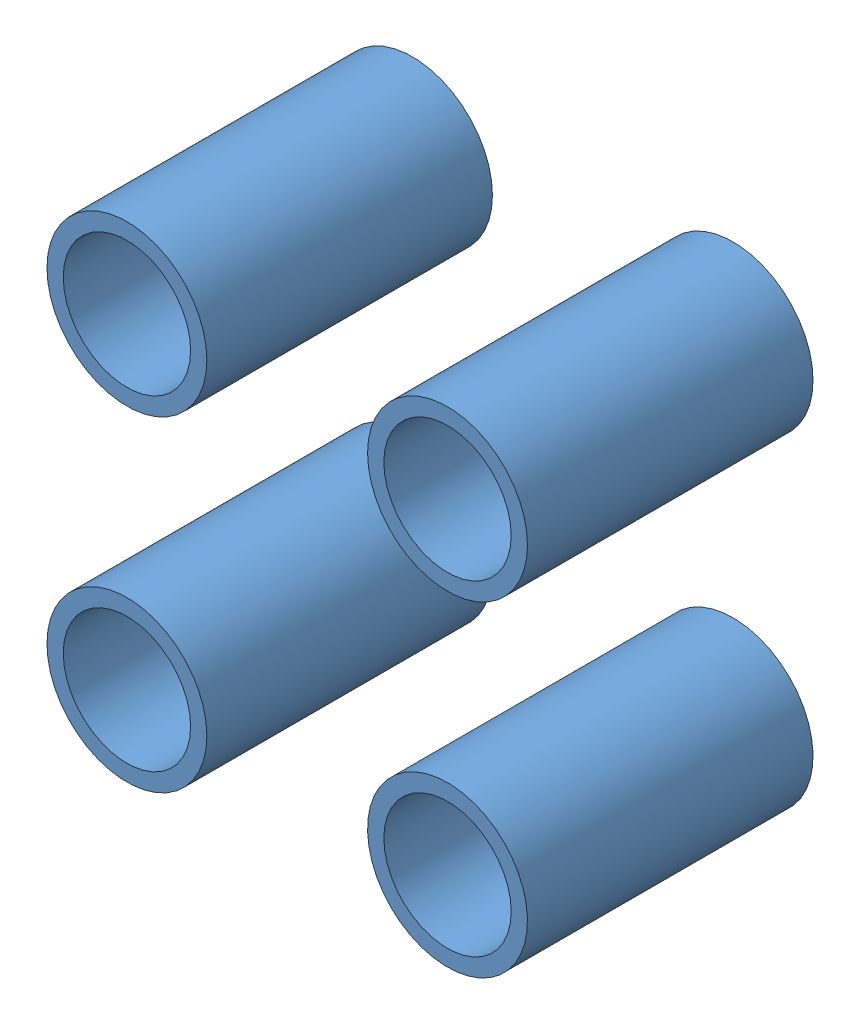
SolidWorks assembly Montagem_adaptador, configuration Valor predeterminado. Lengths in mm.
Overall size (140 140 50).
4 component instances, 1 part files, 16 mates.
Components (placement in the parent):
- Adaptador-1: Adaptador [Valor predeterminado] at (-30.3205 28.5 -38.4696) size (28 28 50)
- Adaptador-2: Adaptador [Valor predeterminado] at (25.8132 28.5 -38.4696) size (28 28 50)
- Adaptador-3: Adaptador [Valor predeterminado] at (27.1649 -26.4347 -38.4696) x (0.400246 -0.916408 0) z (0 0 1) size (28 28 50)
- Adaptador-4: Adaptador [Valor predeterminado] at (-30.3205 -28.5 -38.4696) size (28 28 50)
Mates (geometry in assembly coordinates):
- Coincidente2: coincident: plane of assembly through (0 0 -38.4696) normal (0 0 -1); plane of Adaptador-1 through (-28.0669 28.5 -38.4696) normal (0 0 -1); plane of assembly
- Coincidente3: coincident: plane of assembly through (0 0 -38.4696) normal (0 0 -1); plane of Adaptador-3 through (28.0669 -28.5 -38.4696) normal (0 0 -1); plane of assembly
- Coincidente4: coincident: plane of assembly through (0 0 -38.4696) normal (0 0 -1); plane of Adaptador-4 through (-28.0669 -28.5 -38.4696) normal (0 0 -1); plane of assembly
- Coincidente5: coincident: plane of assembly; plane of Adaptador-2 through (28.0669 28.5 -38.4696) normal (0 0 -1); line of assembly
- Coincidente6: coincident: plane of assembly; plane of Adaptador-1 through (-28.0669 28.5 -38.4696) normal (0 0 -1); line of assembly
- Coincidente7: coincident: plane of assembly; plane of Adaptador-2 through (28.0669 28.5 -38.4696) normal (0 0 -1); line of assembly
- Coincidente8: coincident: plane of assembly; plane of Adaptador-3 through (28.0669 -28.5 -38.4696) normal (0 0 -1); line of assembly
- Perpendicular1: perpendicular: cylinder of assembly; cylinder of Adaptador-3 through (28.0669 -28.5 11.5304) axis (0 0 -1) radius 14; line of assembly
- Distância1: distance = 40 mm: cylinder of assembly; cylinder of Adaptador-3 through (28.0669 -28.5 11.5304) axis (0 0 -1) radius 14; point of assembly
- Distância4: distance = 41 mm: cylinder of assembly; cylinder of Adaptador-3 through (28.0669 -28.5 11.5304) axis (0 0 -1) radius 14; line of assembly
- Distância5: distance = 40 mm: cylinder of assembly; cylinder of Adaptador-4 through (-28.0669 -28.5 11.5304) axis (0 0 -1) radius 14; point of assembly
- Distância6: distance = 41 mm: cylinder of assembly through (-28.0669 -28.5 11.5304) axis (0 0 -1) radius 14; cylinder of Adaptador-4 through (-28.0669 -28.5 11.5304) axis (0 0 -1) radius 14; line of assembly
- Distância7: distance = 40 mm: cylinder of assembly; cylinder of Adaptador-1 through (-28.0669 28.5 11.5304) axis (0 0 -1) radius 14; point of assembly
- Distância8: distance = 41 mm: cylinder of assembly; cylinder of Adaptador-1 through (-28.0669 28.5 11.5304) axis (0 0 -1) radius 14; line of assembly
- Distância9: distance = 40 mm: cylinder of assembly; cylinder of Adaptador-2 through (28.0669 28.5 11.5304) axis (0 0 -1) radius 14; point of assembly
- Distância10: distance = 41 mm: cylinder of assembly; cylinder of Adaptador-2 through (28.0669 28.5 11.5304) axis (0 0 -1) radius 14; line of assembly
